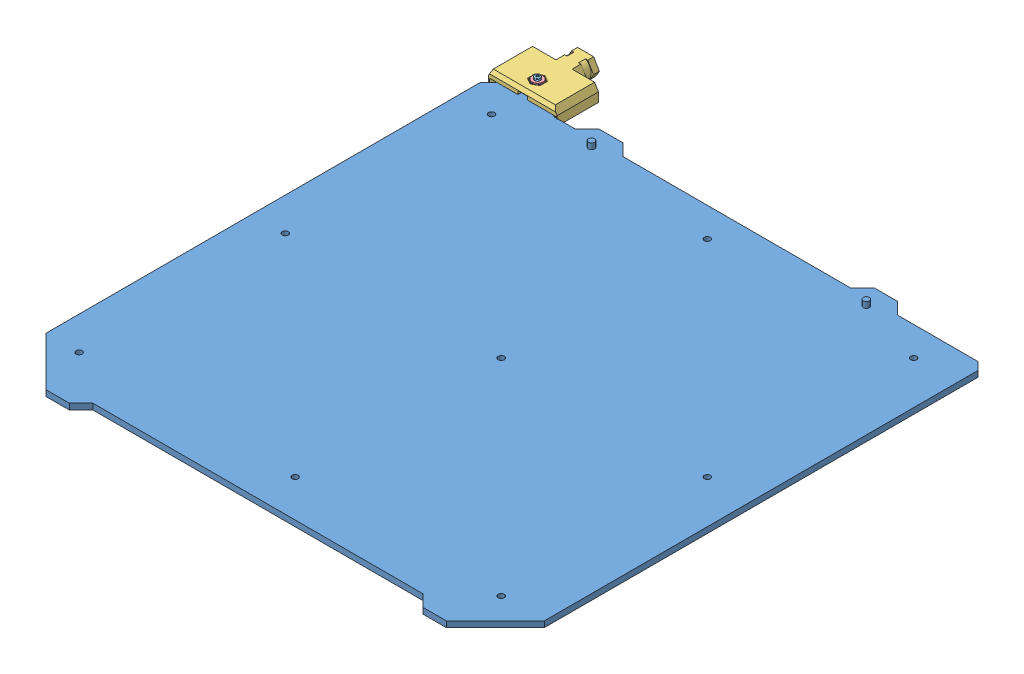
SolidWorks assembly Headbed Assembly, configuration Default. Lengths in mm.
Overall size (253.8 16.07 281.4).
13 component instances, 5 part files, 26 mates.
Components (placement in the parent):
- MK52 Bed-1: MK52 Bed [Default] at (-64.502 153.1745 327.7347) size (253.8 6 264.25)
- 6x6x3t spacer-1: 6x6x3t spacer [Default] at (62.498 147.1745 212.6933) size (6 6 6)
- 6x6x3t spacer-2: 6x6x3t spacer [Default] at (62.498 147.1745 107.6933) size (6 6 6)
- 6x6x3t spacer-3: 6x6x3t spacer [Default] at (-47.502 147.1745 317.6933) size (6 6 6)
- 6x6x3t spacer-4: 6x6x3t spacer [Default] at (-47.502 147.1745 107.6933) x (0.97497 0 -0.222336) z (0.222336 0 0.97497) size (6 6 6)
- 6x6x3t spacer-5: 6x6x3t spacer [Default] at (167.498 147.1745 317.6933) size (6 6 6)
- 6x6x3t spacer-6: 6x6x3t spacer [Default] at (167.498 147.1745 212.6933) size (6 6 6)
- 6x6x3t spacer-7: 6x6x3t spacer [Default] at (167.498 147.1745 107.6933) x (0.999855 0 0.017002) z (-0.017002 0 0.999855) size (6 6 6)
- 6x6x3t spacer-8: 6x6x3t spacer [Default] at (62.498 147.1745 317.6933) size (6 6 6)
- 6x6x3t spacer-9: 6x6x3t spacer [Default] at (-47.502 147.1745 212.6933) size (6 6 6)
- heatbed-cable-cover-1: heatbed-cable-cover [Default] at (-46.0021 153.1745 93.2347) x (1 0 0) z (0 1 0) size (35 32 8)
- M3 Hex Nut-1: M3 Hex Nut [Default] at (-46.0021 160.3745 85.7347) x (1 0 0) z (0 -1 0) size (5.5 6.35 2.74)
- M3-10 Screw-1: M3-10 Screw [93235A313] at (-46.0021 163.1745 85.7347) x (1 0 0) z (0 1 0) size (5.5 5.5 13.21)
Mates (geometry in assembly coordinates):
- Concentric1: concentric anti-aligned: circle of MK52 Bed-1; cylinder of 6x6x3t spacer-3 through (-47.502 153.1745 317.6933) axis (0 -1 0) radius 1.75
- Concentric2: concentric anti-aligned: circle of MK52 Bed-1; cylinder of 6x6x3t spacer-8 through (62.498 153.1745 317.6933) axis (0 -1 0) radius 1.75
- Concentric3: concentric anti-aligned: cylinder of MK52 Bed-1 through (167.498 153.1745 317.6933) axis (0 1 0) radius 1.55; cylinder of 6x6x3t spacer-5 through (167.498 153.1745 317.6933) axis (0 -1 0) radius 1.75
- Concentric4: concentric anti-aligned: circle of MK52 Bed-1; circle of 6x6x3t spacer-9
- Concentric5: concentric anti-aligned: circle of MK52 Bed-1; circle of 6x6x3t spacer-1
- Concentric6: concentric aligned: circle of MK52 Bed-1; circle of 6x6x3t spacer-6
- Concentric7: concentric anti-aligned: circle of MK52 Bed-1; circle of 6x6x3t spacer-4
- Concentric8: concentric anti-aligned: circle of MK52 Bed-1; circle of 6x6x3t spacer-2
- Concentric9: concentric aligned: circle of MK52 Bed-1; circle of 6x6x3t spacer-7
- Coincident1: coincident anti-aligned: plane of MK52 Bed-1 through (-64.502 153.1745 327.7347) normal (0 -1 0); plane of 6x6x3t spacer-8 through (62.498 153.1745 317.6933) normal (0 1 0)
- Coincident2: coincident anti-aligned: plane of MK52 Bed-1 through (-64.502 153.1745 327.7347) normal (0 -1 0); plane of 6x6x3t spacer-5 through (167.498 153.1745 317.6933) normal (0 1 0)
- Coincident3: coincident anti-aligned: plane of MK52 Bed-1 through (-64.502 153.1745 327.7347) normal (0 -1 0); plane of 6x6x3t spacer-3 through (-47.502 153.1745 317.6933) normal (0 1 0)
- Coincident4: coincident anti-aligned: plane of MK52 Bed-1 through (-64.502 153.1745 327.7347) normal (0 -1 0); plane of 6x6x3t spacer-9 through (-47.502 153.1745 212.6933) normal (0 1 0)
- Coincident5: coincident anti-aligned: plane of MK52 Bed-1 through (-64.502 153.1745 327.7347) normal (0 -1 0); plane of 6x6x3t spacer-1 through (62.498 153.1745 212.6933) normal (0 1 0)
- Coincident6: coincident anti-aligned: plane of MK52 Bed-1 through (-64.502 153.1745 327.7347) normal (0 -1 0); plane of 6x6x3t spacer-2 through (62.498 153.1745 107.6933) normal (0 1 0)
- Coincident7: coincident anti-aligned: plane of MK52 Bed-1 through (-64.502 153.1745 327.7347) normal (0 -1 0); plane of 6x6x3t spacer-6 through (167.498 153.1745 212.6933) normal (0 1 0)
- Coincident8: coincident anti-aligned: plane of MK52 Bed-1 through (-64.502 153.1745 327.7347) normal (0 -1 0); plane of 6x6x3t spacer-4 through (-47.502 153.1745 107.6933) normal (0 1 0)
- Coincident9: coincident anti-aligned: plane of MK52 Bed-1 through (-64.502 153.1745 327.7347) normal (0 -1 0); plane of 6x6x3t spacer-7 through (167.498 153.1745 107.6933) normal (0 1 0)
- Concentric10: concentric anti-aligned: circle of MK52 Bed-1; circle of heatbed-cable-cover-1
- Coincident11: coincident aligned: plane of MK52 Bed-1 through (-64.502 153.1745 327.7347) normal (0 -1 0); plane of heatbed-cable-cover-1 through (-60.0021 153.1745 83.2347) normal (0 -1 0)
- Parallel1: parallel aligned: plane of MK52 Bed-1 through (-64.402 156.1745 327.7347) normal (-1 0 0); plane of heatbed-cable-cover-1 through (-63.5021 153.1745 93.2347) normal (-1 0 0)
- Concentric11: concentric aligned: circle of heatbed-cable-cover-1; circle of M3 Hex Nut-1
- Coincident12: coincident anti-aligned: plane of heatbed-cable-cover-1 through (-46.0021 159.1745 82.4347) normal (0 1 0); plane of M3 Hex Nut-1 through (-46.0021 159.1745 85.7347) normal (0 -1 0)
- Parallel2: parallel anti-aligned: plane of heatbed-cable-cover-1 through (-48.8599 159.1745 84.0847) normal (1 0 0); plane of M3 Hex Nut-1 through (-48.7521 159.1745 87.3224) normal (-1 0 0)
- Concentric12: concentric aligned: cylinder of MK52 Bed-1 through (-46.0021 153.1745 85.7347) axis (0 1 0) radius 1.55; cylinder of M3-10 Screw-1 through (-46.0021 150.1745 85.7347) axis (0 1 0) radius 2.75
- Coincident14: coincident anti-aligned: plane of MK52 Bed-1 through (-64.502 153.1745 327.7347) normal (0 -1 0); plane of M3-10 Screw-1 through (-46.0021 153.1745 85.7347) normal (0 1 0)
